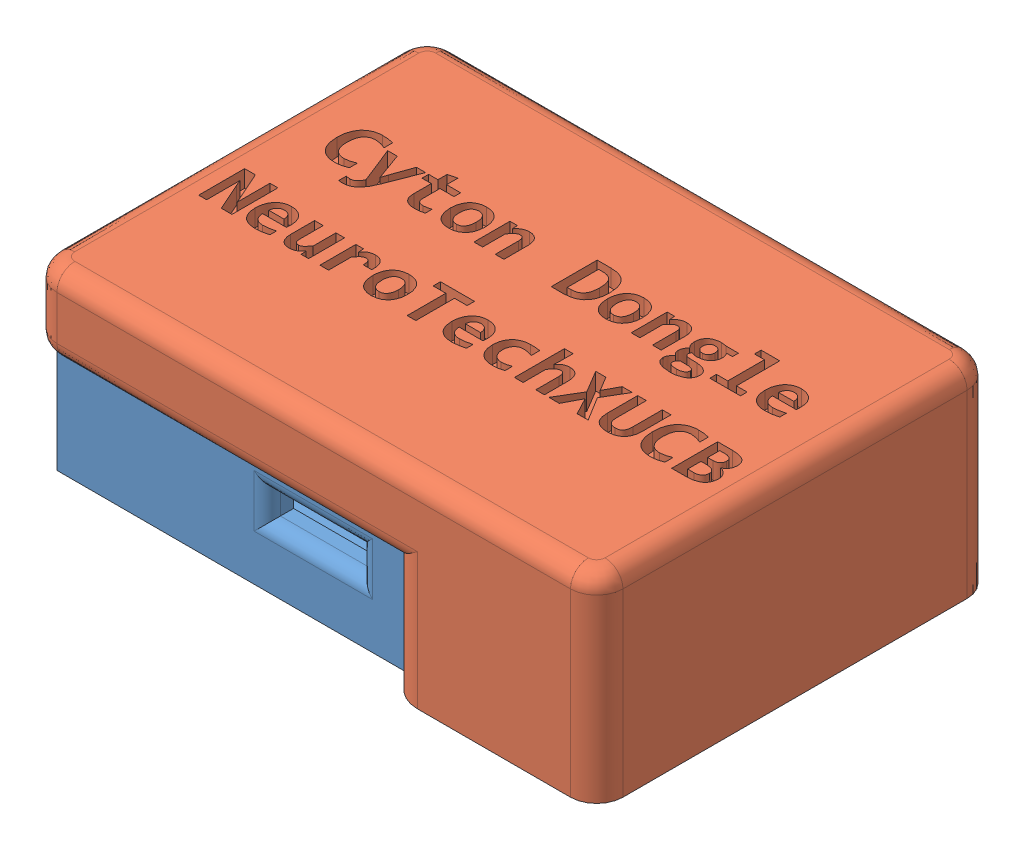
SolidWorks assembly ensamble dongle cyton, configuration Predeterminado. Lengths in mm.
Overall size (43.17 15.1 30.2).
2 component instances, 2 part files, 2 mates.
Components (placement in the parent):
- tapa dongle cyton-1: tapa dongle cyton [Predeterminado] at origin size (41.1 13 26.1)
- inferior dongle cyton-1: inferior dongle cyton [Predeterminado] at (-0.0179 0 -0.1) size (43.17 15.1 30.2)
Mates (geometry in assembly coordinates):
- Coincidente1: coincident anti-aligned: plane of tapa dongle cyton-1 through (18.55 11 13.05) normal (0 0 1); plane of inferior dongle cyton-1 through (-20.5679 63.6275 13.05) normal (0 0 -1)
- Coincidente2: coincident aligned: plane of tapa dongle cyton-1 through (0 -2 0) normal (0 -1 0); plane of inferior dongle cyton-1 through (-0.0179 -2 -0.1) normal (0 -1 0)
